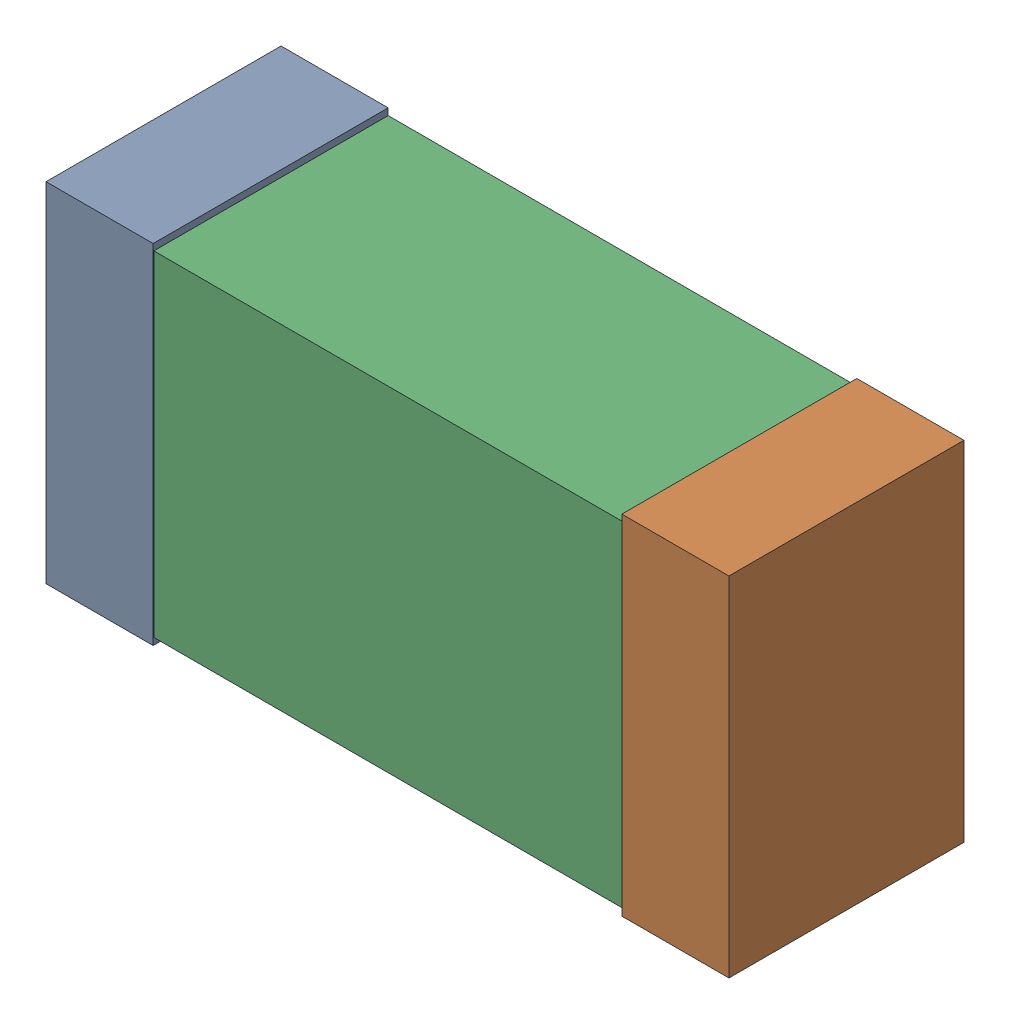
SolidWorks assembly R6, configuration Default. Lengths in mm.
Overall size (1.02 0.52 0.35).
6 component instances, 2 part files, 0 mates.
Components (placement in the parent):
- 870940480-1: 870940480 [Default] at (55.4238 26.4392 0) size (0.16 0.52 0.35)
  - Extruded-1: Extruded [Default] at origin size (0.16 0.52 0.35)
- 870940480-2: 870940480 [Default] at (56.2838 26.4392 0) size (0.16 0.52 0.35)
  - Extruded-1: Extruded [Default] at origin size (0.16 0.52 0.35)
- 870940640-1: 870940640 [Default] at (55.8538 26.4392 0) size (1 0.5 0.35)
  - Extruded_2-1: Extruded_2 [Default] at origin size (1 0.5 0.35)
